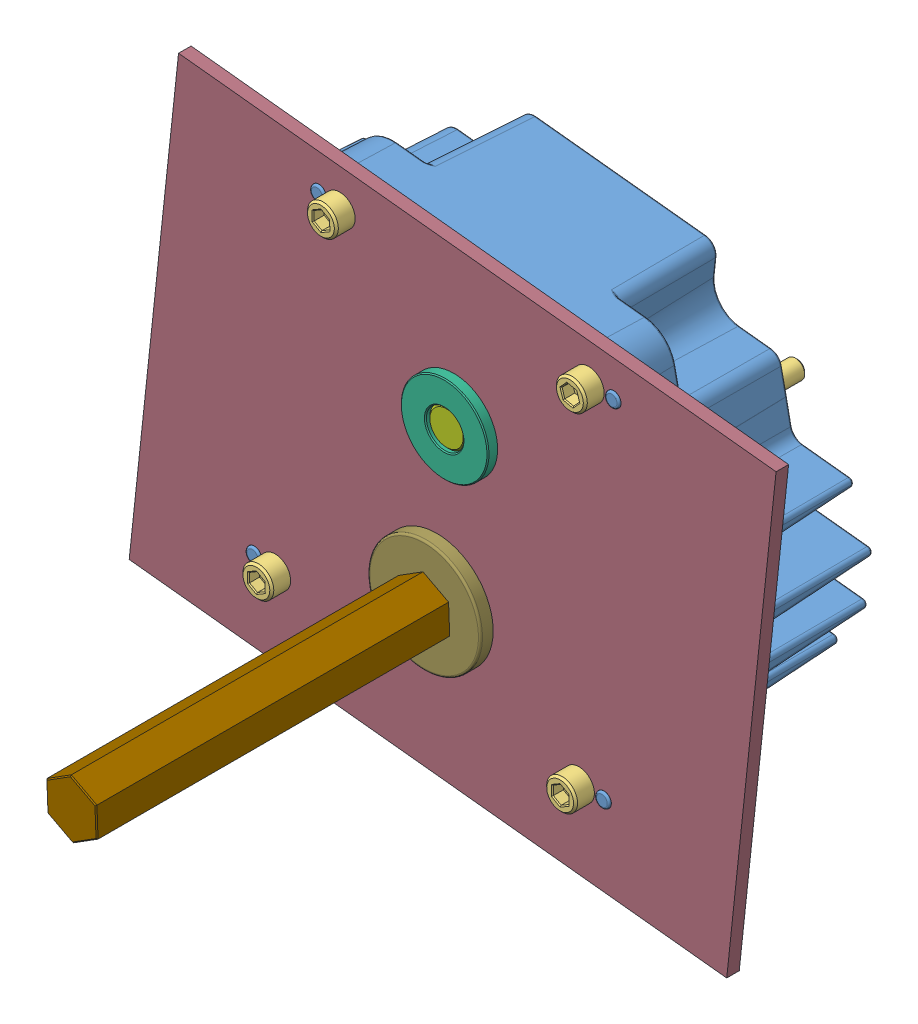
SolidWorks assembly middle gearbox, configuration Default. Lengths in mm.
Overall size (164.06 133.6 142.29).
27 component instances, 13 part files, 60 mates.
Components (placement in the parent):
- TBMiniHousing-1: TBMiniHousing [Default] at (-222.5246 101.0905 59.9028) x (0.994368 -0.105981 0) z (0 0 1) size (139.9 118.55 41.54)
- Washer_5-16-1: Washer_5-16 [Default] at (-181.0223 124.9966 68.488) x (-0.418041 0.908428 0) z (0 0 -1) size (17.53 17.53 1.47)
- Screw_SHCS_10-32x0.625-1: Screw_SHCS_10-32x0.625 [Default] at (-183.4725 167.916 103.667) x (0.740711 -0.671824 0) z (-0.671824 -0.740711 0) size (7.82 20.65 7.82)
- Screw_SHCS_10-32x0.625-2: Screw_SHCS_10-32x0.625 [Default] at (-262.9822 86.9867 103.667) x (0.507484 -0.861661 0) z (-0.861661 -0.507484 0) size (7.82 20.65 7.82)
- Screw_SHCS_10-32x0.625-3: Screw_SHCS_10-32x0.625 [Default] at (-185.9485 78.7764 103.667) x (0.507484 -0.861661 0) z (-0.861661 -0.507484 0) size (7.82 20.65 7.82)
- Screw_SHCS_10-32x0.625-4: Screw_SHCS_10-32x0.625 [Default] at (-246.6148 174.6458 103.667) x (0.507484 -0.861661 0) z (-0.861661 -0.507484 0) size (7.82 20.65 7.82)
- Screw_SHCS_10-32x0.625-5: Screw_SHCS_10-32x0.625 [Default] at (-178.3304 150.2535 71.79) x (-0.564778 -0.825243 0) z (-0.825243 0.564778 0) size (7.82 20.65 7.82)
- CIMGear_14t8mm-2: CIMGear_14t8mm [Default] at (-181.0223 124.9966 82.6612) x (-0.082762 0.996569 0) z (0 0 -1) size (20.03 20.32 12.7)
- Washer_5-16-2: Washer_5-16 [Default] at (-258.056 133.2069 67.0148) x (0.718484 -0.695544 0) z (0 0 1) size (17.53 17.53 1.47)
- NylockNut_10-32-1: NylockNut_10-32 [Default] at (-185.9485 78.7764 89.8748) x (-0.589485 -0.807779 0) z (0 0 -1) size (10.18 11.01 7.1)
- Washer_5-16-3: Washer_5-16 [Default] at (-258.056 133.2069 68.488) x (-0.990116 0.140253 0) z (0 0 1) size (17.53 17.53 1.47)
- Washer_5-16-4: Washer_5-16 [Default] at (-181.0223 124.9966 69.9612) x (0.897267 -0.441488 0) z (0 0 -1) size (17.53 17.53 1.47)
- NylockNut_10-32-2: NylockNut_10-32 [Default] at (-246.6148 174.6458 89.8748) x (0.588447 0.808535 0) z (0 0 -1) size (10.18 11.01 7.1)
- NylockNut_10-32-3: NylockNut_10-32 [Default] at (-262.9822 86.9867 89.8748) x (0.589485 0.807779 0) z (0 0 -1) size (10.18 11.01 7.1)
- Bearing_FR6ZZ-1: Bearing_FR6ZZ [Default] at (-223.4216 150.951 93.6594) x (-0.893862 0.448342 0) z (0 0 1) size (24.69 24.69 7.16)
- TBMiniSmallHexShaft-1: TBMiniSmallHexShaft [Default] at (-256.9641 123.8468 93.8626) x (-0.674239 -0.738513 0) z (-0.738513 0.674239 0) size (11 38.23 9.52)
- NylockNut_10-32-4: NylockNut_10-32 [Default] at (-183.4725 167.916 89.8748) x (0.994368 -0.105981 0) z (0 0 -1) size (10.18 11.01 7.1)
- RetainingClip-1: RetainingClip [Default] at (-181.0223 124.9966 82.6612) x (0 0 1) z (-1 0 0) size (1.09 14.83 14.83)
- TBMiniHexOutputShaft-1: TBMiniHexOutputShaft [Default] at (-181.2271 107.3999 93.9388) x (0.846172 0.53291 0) z (0.53291 -0.846172 0) size (14.66 142.29 12.7)
- Screw_SHCS_10-32x0.625-6: Screw_SHCS_10-32x0.625 [Default] at (-255.3641 158.4639 71.79) x (-0.966277 -0.257503 0) z (-0.257503 0.966277 0) size (7.82 20.65 7.82)
- ExternalKlipring-1: ExternalKlipring [Default] at (-222.5246 101.0905 81.823) x (0.996411 -0.084651 0) z (0 0 1) size (19.07 20.96 1.27)
- Bearing_R6ZZ-1: Bearing_R6ZZ [Default] at (-222.5246 101.0905 61.4268) x (-0.661529 0.74992 0) z (0 0 1) size (22.23 22.23 7.11)
- Bearing_R6ZZ-2: Bearing_R6ZZ [Default] at (-218.2095 141.5774 61.4268) x (0.958138 -0.286306 0) z (0 0 1) size (22.23 22.23 7.11)
- HexBearing_FR8ZZ-1: HexBearing_FR8ZZ [Default] at (-222.5246 101.0905 101.5867) x (0.846172 0.53291 0) z (0 0 -1) size (31.12 31.12 7.93)
- Screw_SHCS_10-32x0.625-7: Screw_SHCS_10-32x0.625 [Default] at (-183.7142 99.7396 71.79) x (-0.564778 -0.825243 0) z (-0.825243 0.564778 0) size (7.82 20.65 7.82)
- Screw_SHCS_10-32x0.625-8: Screw_SHCS_10-32x0.625 [Default] at (-260.7479 107.95 71.79) x (-0.99652 0.083357 0) z (0.083357 0.99652 0) size (7.82 20.65 7.82)
- 6x6 gearbox cover-1: 6x6 gearbox cover [Default] at (-215.0227 142.1513 95.191) x (0.994368 -0.105981 0) z (0 0 1) size (152.4 118.11 3.17)
Mates (geometry in assembly coordinates):
- Concentric1: concentric anti-aligned: circle of TBMiniHousing-1; circle of NylockNut_10-32-1
- Coincident1: coincident anti-aligned: plane of TBMiniHousing-1 through (-195.7769 79.8239 89.8748) normal (0 0 -1); plane of NylockNut_10-32-1 through (-185.9485 78.7764 89.8748) normal (0 0 1)
- Parallel1: parallel: line of TBMiniHousing-1 through (-180.8173 81.4602 85.3028) axis (-0.807779 0.589485 0); plane of NylockNut_10-32-1 through (-183.1411 82.6234 87.8904) normal (0.589485 0.807779 0)
- Concentric2: concentric aligned: circle of TBMiniHousing-1; circle of NylockNut_10-32-2
- Parallel2: parallel: line of TBMiniHousing-1 through (-246.2785 180.1996 85.5479) axis (-0.913878 -0.405988 0); plane of NylockNut_10-32-2 through (-248.5484 178.9981 87.8904) normal (-0.405988 0.913878 0)
- Coincident2: coincident anti-aligned: plane of TBMiniHousing-1 through (-256.4432 175.6933 89.8748) normal (0 0 -1); plane of NylockNut_10-32-2 through (-246.6148 174.6458 89.8748) normal (0 0 1)
- Coincident3: coincident anti-aligned: plane of TBMiniHousing-1 through (-182.8668 173.5988 89.8748) normal (0 0 -1); plane of NylockNut_10-32-4 through (-183.4725 167.916 89.8748) normal (0 0 1)
- Concentric3: concentric anti-aligned: circle of TBMiniHousing-1; circle of NylockNut_10-32-4
- Parallel3: parallel: line of TBMiniHousing-1 through (-178.5741 164.8261 85.3028) axis (0.105981 0.994368 0); plane of NylockNut_10-32-4 through (-178.7368 167.4112 87.8904) normal (0.994368 -0.105981 0)
- Concentric4: concentric aligned: circle of TBMiniHousing-1; circle of NylockNut_10-32-3
- Coincident4: coincident anti-aligned: plane of TBMiniHousing-1 through (-272.8106 88.0342 89.8748) normal (0 0 -1); plane of NylockNut_10-32-3 through (-262.9822 86.9867 89.8748) normal (0 0 1)
- Distance1: distance = 3.175 mm anti-aligned: plane of TBMiniHousing-1 through (-222.5246 101.0905 95.7168) normal (0 0 1); plane of Screw_SHCS_10-32x0.625-1 through (-183.4725 167.916 98.8918) normal (0 0 -1)
- Concentric5: concentric anti-aligned: cylinder of Bearing_FR6ZZ-1 through (-218.2095 141.5774 95.1834) axis (0 0 1) radius 4.7625; cylinder of TBMiniSmallHexShaft-1 through (-218.2095 141.5774 100.2126) axis (0 0 -1) radius 4.7498
- Coincident5: coincident anti-aligned: plane of TBMiniHousing-1 through (-183.4725 167.916 67.0148) normal (0 0 1); plane of Screw_SHCS_10-32x0.625-8 through (-260.7479 107.95 67.0148) normal (0 0 -1)
- Coincident6: coincident aligned: circle of Washer_5-16-1; circle of Washer_5-16-4
- Concentric6: concentric anti-aligned: cylinder of TBMiniHousing-1 through (-178.3304 150.2535 95.7168) axis (0 0 1) radius 2.5527; circle of Screw_SHCS_10-32x0.625-5
- Parallel4: parallel: line of TBMiniHousing-1 through (-263.9736 81.2817 85.3028) axis (-0.807779 0.589485 0); plane of NylockNut_10-32-3 through (-265.7897 83.1397 87.8904) normal (-0.589485 -0.807779 0)
- Coincident7: coincident anti-aligned: plane of TBMiniHousing-1 through (-183.4725 167.916 67.0148) normal (0 0 1); plane of Screw_SHCS_10-32x0.625-5 through (-178.3304 150.2535 67.0148) normal (0 0 -1)
- Concentric7: concentric anti-aligned: cylinder of TBMiniHousing-1 through (-258.056 133.2069 95.7168) axis (0 0 1) radius 10.414; circle of Washer_5-16-2
- Coincident9: coincident anti-aligned: plane of TBMiniSmallHexShaft-1 through (-219.8728 146.8191 68.5388) normal (0 0 -1); plane of Bearing_R6ZZ-2 through (-218.2095 141.5774 68.5388) normal (0 0 1)
- Coincident10: coincident anti-aligned: plane of Bearing_FR6ZZ-1 through (-218.2095 141.5774 93.6594) normal (0 0 -1); plane of TBMiniSmallHexShaft-1 through (-214.5017 145.6386 93.6594) normal (0 0 1)
- Coincident11: coincident aligned: plane of Screw_SHCS_10-32x0.625-1 through (-183.4725 167.916 103.667) normal (0 0 1); plane of Screw_SHCS_10-32x0.625-4 through (-246.6148 174.6458 103.667) normal (0 0 1)
- Coincident12: coincident aligned: plane of Screw_SHCS_10-32x0.625-1 through (-183.4725 167.916 103.667) normal (0 0 1); plane of Screw_SHCS_10-32x0.625-3 through (-185.9485 78.7764 103.667) normal (0 0 1)
- Coincident13: coincident aligned: circle of CIMGear_14t8mm-2; plane of Washer_5-16-4 through (-181.0223 124.9966 69.9612) normal (0 0 1)
- Concentric8: concentric aligned: cylinder of TBMiniHousing-1 through (-218.2095 141.5774 61.4268) axis (0 0 -1) radius 11.1061; cylinder of Bearing_R6ZZ-2 through (-218.2095 141.5774 68.5388) axis (0 0 -1) radius 11.1125
- Concentric9: concentric aligned: cylinder of TBMiniHousing-1 through (-255.3641 158.4639 95.7168) axis (0 0 1) radius 2.5527; circle of Screw_SHCS_10-32x0.625-6
- Concentric10: concentric aligned: cylinder of TBMiniHousing-1 through (-183.7142 99.7396 95.7168) axis (0 0 1) radius 2.5527; cylinder of Screw_SHCS_10-32x0.625-7 through (-183.7142 99.7396 51.1398) axis (0 0 1) radius 2.3876
- Coincident15: coincident anti-aligned: plane of Washer_5-16-2 through (-258.056 133.2069 68.488) normal (0 0 1); plane of Washer_5-16-3 through (-258.056 133.2069 68.488) normal (0 0 -1)
- Coincident16: coincident anti-aligned: plane of TBMiniHousing-1 through (-218.2095 141.5774 61.4268) normal (0 0 1); plane of Bearing_R6ZZ-2 through (-218.2095 141.5774 61.4268) normal (0 0 -1)
- Concentric12: concentric aligned: cylinder of CIMGear_14t8mm-2 through (-181.0223 124.9966 69.9612) axis (0 0 1) radius 4; circle of Washer_5-16-4
- Coincident17: coincident anti-aligned: plane of TBMiniHousing-1 through (-183.4725 167.916 67.0148) normal (0 0 1); plane of Washer_5-16-2 through (-258.056 133.2069 67.0148) normal (0 0 -1)
- Concentric13: concentric aligned: cylinder of TBMiniHousing-1 through (-260.7479 107.95 95.7168) axis (0 0 1) radius 2.5527; cylinder of Screw_SHCS_10-32x0.625-8 through (-260.7479 107.95 51.1398) axis (0 0 1) radius 2.3876
- Coincident18: coincident aligned: plane of Screw_SHCS_10-32x0.625-1 through (-183.4725 167.916 98.8918) normal (0 0 -1); plane of Screw_SHCS_10-32x0.625-2 through (-262.9822 86.9867 98.8918) normal (0 0 -1)
- Coincident19: coincident anti-aligned: plane of TBMiniHousing-1 through (-183.4725 167.916 67.0148) normal (0 0 1); plane of Screw_SHCS_10-32x0.625-6 through (-255.3641 158.4639 67.0148) normal (0 0 -1)
- Coincident20: coincident anti-aligned: plane of TBMiniHousing-1 through (-183.4725 167.916 67.0148) normal (0 0 1); plane of Screw_SHCS_10-32x0.625-7 through (-183.7142 99.7396 67.0148) normal (0 0 -1)
- Concentric15: concentric aligned: cylinder of TBMiniHousing-1 through (-181.0223 124.9966 95.7168) axis (0 0 1) radius 10.414; cylinder of Washer_5-16-1 through (-181.0223 124.9966 67.0148) axis (0 0 1) radius 4.3942
- Coincident21: coincident aligned: plane of Screw_SHCS_10-32x0.625-1 through (-183.4725 167.916 98.8918) normal (0 0 -1); plane of Screw_SHCS_10-32x0.625-4 through (-246.6148 174.6458 98.8918) normal (0 0 -1)
- Concentric16: concentric aligned: cylinder of Washer_5-16-2 through (-258.056 133.2069 68.488) axis (0 0 -1) radius 8.763; cylinder of Washer_5-16-3 through (-258.056 133.2069 69.9612) axis (0 0 -1) radius 8.763
- Coincident22: coincident anti-aligned: plane of TBMiniHousing-1 through (-183.4725 167.916 67.0148) normal (0 0 1); plane of Washer_5-16-1 through (-181.0223 124.9966 67.0148) normal (0 0 -1)
- Coincident23: coincident aligned: plane of Screw_SHCS_10-32x0.625-3 through (-185.9485 78.7764 98.8918) normal (0 0 -1); plane of Screw_SHCS_10-32x0.625-4 through (-246.6148 174.6458 98.8918) normal (0 0 -1)
- Coincident24: coincident anti-aligned: plane of CIMGear_14t8mm-2 through (-181.0223 124.9966 82.6612) normal (0 0 1); circle of RetainingClip-1
- Concentric17: concentric anti-aligned: cylinder of TBMiniSmallHexShaft-1 through (-218.2095 141.5774 61.9856) axis (0 0 1) radius 4.7498; cylinder of Bearing_R6ZZ-2 through (-218.2095 141.5774 68.5388) axis (0 0 -1) radius 11.1125
- Concentric18: concentric aligned: circle of CIMGear_14t8mm-2; circle of RetainingClip-1
- Concentric20: concentric anti-aligned: cylinder of TBMiniHousing-1 through (-222.5246 101.0905 95.7168) axis (0 0 1) radius 5.08; cylinder of Bearing_R6ZZ-1 through (-222.5246 101.0905 68.5388) axis (0 0 -1) radius 11.1125
- Coincident25: coincident anti-aligned: plane of TBMiniHousing-1 through (-222.5246 101.0905 61.4268) normal (0 0 1); plane of Bearing_R6ZZ-1 through (-222.5246 101.0905 61.4268) normal (0 0 -1)
- Coincident26: coincident aligned: plane of Bearing_FR6ZZ-1 through (-218.2095 141.5774 95.1834) normal (0 0 1); plane of HexBearing_FR8ZZ-1 through (-210.7036 108.5352 95.1834) normal (0 0 1)
- Concentric21: concentric aligned: cone of TBMiniHousing-1 through (-183.4725 167.916 90.365) axis (0 0 1); cylinder of Screw_SHCS_10-32x0.625-1 through (-183.4725 167.916 98.8918) axis (0 0 1) radius 3.9116
- Concentric22: concentric aligned: cone of TBMiniHousing-1 through (-246.6148 174.6458 90.365) axis (0 0 1); cylinder of Screw_SHCS_10-32x0.625-4 through (-246.6148 174.6458 98.8918) axis (0 0 1) radius 3.9116
- Coincident28: coincident aligned: plane of Screw_SHCS_10-32x0.625-2 through (-262.9822 86.9867 103.667) normal (0 0 1); plane of Screw_SHCS_10-32x0.625-4 through (-246.6148 174.6458 103.667) normal (0 0 1)
- Concentric23: concentric aligned: cone of TBMiniHousing-1 through (-262.9822 86.9867 90.365) axis (0 0 1); cylinder of Screw_SHCS_10-32x0.625-2 through (-262.9822 86.9867 83.0168) axis (0 0 1) radius 2.3876
- Concentric26: concentric anti-aligned: cylinder of Bearing_R6ZZ-1 through (-222.5246 101.0905 68.5388) axis (0 0 -1) radius 11.1125; cylinder of HexBearing_FR8ZZ-1 through (-222.5246 101.0905 93.6594) axis (0 0 1) radius 14.2875
- Concentric27: concentric anti-aligned: cylinder of TBMiniHexOutputShaft-1 through (-222.5246 101.0905 61.4268) axis (0 0 1) radius 4.7498; cylinder of Bearing_R6ZZ-1 through (-222.5246 101.0905 68.5388) axis (0 0 -1) radius 4.7625
- Coincident32: coincident anti-aligned: plane of TBMiniHexOutputShaft-1 through (-222.8064 108.4174 68.5388) normal (-0.53291 0.846172 0); plane of HexBearing_FR8ZZ-1 through (-222.8064 108.4174 93.6594) normal (0.53291 -0.846172 0)
- Concentric28: concentric aligned: cone of TBMiniHousing-1 through (-185.9485 78.7764 90.365) axis (0 0 1); cylinder of Screw_SHCS_10-32x0.625-3 through (-185.9485 78.7764 98.8918) axis (0 0 1) radius 3.9116
- Concentric29: concentric anti-aligned: cylinder of TBMiniHexOutputShaft-1 through (-222.5246 101.0905 68.5388) axis (0 0 1) radius 5.588; cylinder of ExternalKlipring-1 through (-222.5246 101.0905 83.093) axis (0 0 -1) radius 5.1562
- Coincident34: coincident anti-aligned: plane of TBMiniHexOutputShaft-1 through (-208.5467 109.8936 81.823) normal (0 0 1); plane of ExternalKlipring-1 through (-222.5246 101.0905 81.823) normal (0 0 -1)
- Coincident35: coincident anti-aligned: plane of TBMiniHexOutputShaft-1 through (-215.7567 90.3441 68.5388) normal (0 0 -1); plane of Bearing_R6ZZ-1 through (-222.5246 101.0905 68.5388) normal (0 0 1)
- Coincident36: coincident anti-aligned: line of TBMiniHousing-1 through (-245.6632 183.5745 95.191) axis (0.994368 -0.105981 0); line of 6x6 gearbox cover-1 through (-136.4831 171.9379 95.191) axis (-0.994368 0.105981 0)
- Parallel7: parallel anti-aligned: plane of TBMiniHousing-1 through (-222.5246 101.0905 95.7168) normal (0 0 1); plane of 6x6 gearbox cover-1 through (-215.0227 142.1513 95.191) normal (0 0 -1)
- Lock1: lock: unknown of TBMiniHousing-1; unknown of 6x6 gearbox cover-1
